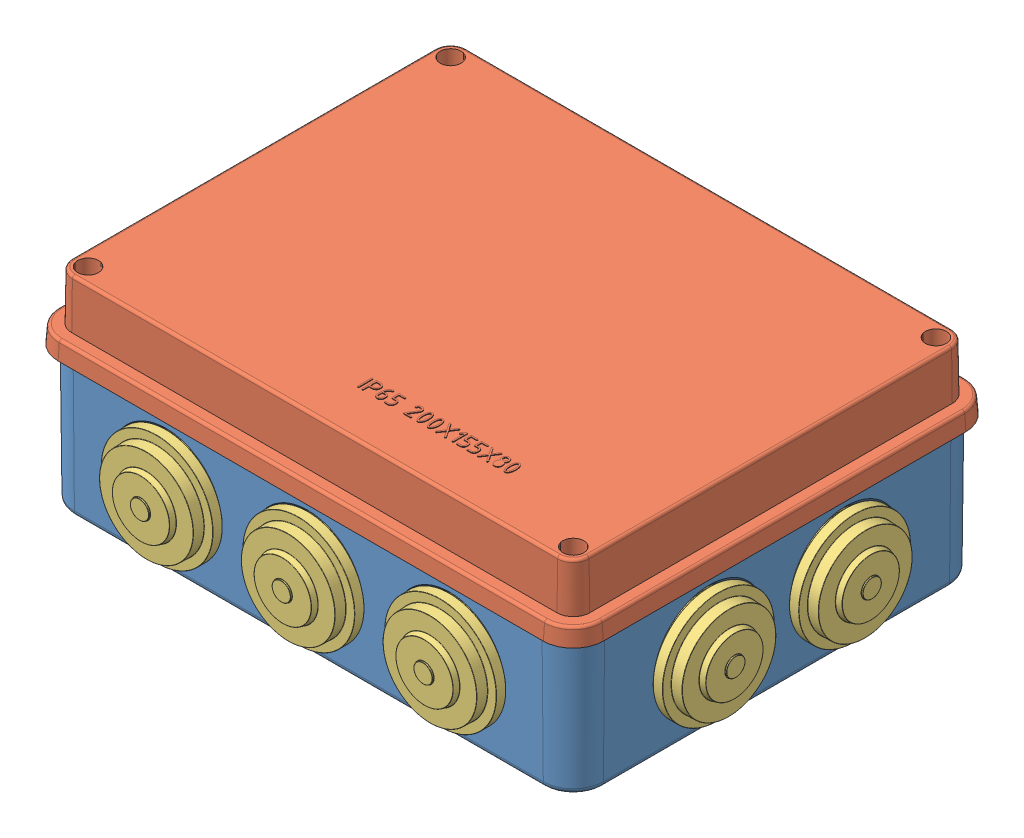
SolidWorks assembly ENCLOSURE ip67, configuration 默认. Lengths in mm.
Overall size (214.7 76.3 169.68).
17 component instances, 5 part files, 0 mates.
Components (placement in the parent):
- ENCLOSURE, IP65 ELECTRICAL ENCLOSURE, 200 mm x 155 mm x 80 mm_1-1: ENCLOSURE, IP65 ELECTRICAL ENCLOSURE, 200 mm x 155 mm x 80 mm_1 [默认] at origin size (197.16 54.12 152.16)
- ENCLOSURE COVER, IP65 ELECTRICAL ENCLOSURE, 200 mm x 155 mm x 80 mm_1-1: ENCLOSURE COVER, IP65 ELECTRICAL ENCLOSURE, 200 mm x 155 mm x 80 mm_1 [默认] at (0 49.6 0) size (200 24.71 155)
- GROMMET, IP65 ELECTRICAL ENCLOSURE, 200 mm x 155 mm x 80 mm_1-1: GROMMET, IP65 ELECTRICAL ENCLOSURE, 200 mm x 155 mm x 80 mm_1 [默认] at (0 24.6073 66.8362) x (-0.999687 0.025034 0.000241) z (0 -0.009615 0.999954) size (41 41 17.8)
- GROMMET, IP65 ELECTRICAL ENCLOSURE, 200 mm x 155 mm x 80 mm_1-2: GROMMET, IP65 ELECTRICAL ENCLOSURE, 200 mm x 155 mm x 80 mm_1 [默认] at (52 24.6073 66.8362) x (-0.999687 0.025034 0.000241) z (0 -0.009615 0.999954) size (41 41 17.8)
- GROMMET, IP65 ELECTRICAL ENCLOSURE, 200 mm x 155 mm x 80 mm_1-3: GROMMET, IP65 ELECTRICAL ENCLOSURE, 200 mm x 155 mm x 80 mm_1 [默认] at (-52 24.6073 66.8362) x (-0.999687 0.025034 0.000241) z (0 -0.009615 0.999954) size (41 41 17.8)
- GROMMET, IP65 ELECTRICAL ENCLOSURE, 200 mm x 155 mm x 80 mm_1-4: GROMMET, IP65 ELECTRICAL ENCLOSURE, 200 mm x 155 mm x 80 mm_1 [默认] at (0 24.6073 -66.8362) x (0.999687 -0.025034 0.000241) z (0 -0.009615 -0.999954) size (41 41 17.8)
- GROMMET, IP65 ELECTRICAL ENCLOSURE, 200 mm x 155 mm x 80 mm_1-5: GROMMET, IP65 ELECTRICAL ENCLOSURE, 200 mm x 155 mm x 80 mm_1 [默认] at (52 24.6073 -66.8362) x (0.999687 -0.025034 0.000241) z (0 -0.009615 -0.999954) size (41 41 17.8)
- GROMMET, IP65 ELECTRICAL ENCLOSURE, 200 mm x 155 mm x 80 mm_1-6: GROMMET, IP65 ELECTRICAL ENCLOSURE, 200 mm x 155 mm x 80 mm_1 [默认] at (-52 24.6073 -66.8362) x (0.999687 -0.025034 0.000241) z (0 -0.009615 -0.999954) size (41 41 17.8)
- GROMMET, IP65 ELECTRICAL ENCLOSURE, 200 mm x 155 mm x 80 mm_1-7: GROMMET, IP65 ELECTRICAL ENCLOSURE, 200 mm x 155 mm x 80 mm_1 [默认] at (89.3342 24.391 -25) x (-0.009571 -0.995424 -0.095073) z (0.999954 -0.009615 0) size (41 41 17.8)
- GROMMET, IP65 ELECTRICAL ENCLOSURE, 200 mm x 155 mm x 80 mm_1-8: GROMMET, IP65 ELECTRICAL ENCLOSURE, 200 mm x 155 mm x 80 mm_1 [默认] at (89.3342 24.391 25) x (0.009571 0.995424 -0.095073) z (0.999954 -0.009615 0) size (41 41 17.8)
- GROMMET, IP65 ELECTRICAL ENCLOSURE, 200 mm x 155 mm x 80 mm_1-9: GROMMET, IP65 ELECTRICAL ENCLOSURE, 200 mm x 155 mm x 80 mm_1 [默认] at (-89.3342 24.391 -25) x (-0.009571 0.995424 0.095073) z (-0.999954 -0.009615 0) size (41 41 17.8)
- GROMMET, IP65 ELECTRICAL ENCLOSURE, 200 mm x 155 mm x 80 mm_1-10: GROMMET, IP65 ELECTRICAL ENCLOSURE, 200 mm x 155 mm x 80 mm_1 [默认] at (-89.3342 24.391 25) x (0.009571 -0.995424 0.095073) z (-0.999954 -0.009615 0) size (41 41 17.8)
- O-RING, IP65 ELECTRICAL ENCLOSURE, 200 mm x 155 mm x 80 mm_1-1: O-RING, IP65 ELECTRICAL ENCLOSURE, 200 mm x 155 mm x 80 mm_1 [默认] at (0 52.1 0) x (1 0 0) z (0 -1 0) size (195 150 3)
- cross ph tapping 968_din_Screw DIN 968-ST2.9x13-C-H-N-1: cross ph tapping 968_din_Screw DIN 968-ST2.9x13-C-H-N [默认] at (-89 54.1 66.5) x (0 -1 0) z (-0.071053 0 0.997473) size (15.35 7.5 7.5)
- cross ph tapping 968_din_Screw DIN 968-ST2.9x13-C-H-N-2: cross ph tapping 968_din_Screw DIN 968-ST2.9x13-C-H-N [默认] at (89 54.1 66.5) x (0 -1 0) z (-0.071053 0 -0.997473) size (15.35 7.5 7.5)
- cross ph tapping 968_din_Screw DIN 968-ST2.9x13-C-H-N-3: cross ph tapping 968_din_Screw DIN 968-ST2.9x13-C-H-N [默认] at (-89 54.1 -66.5) x (0 -1 0) z (0.071053 0 0.997473) size (15.35 7.5 7.5)
- cross ph tapping 968_din_Screw DIN 968-ST2.9x13-C-H-N-4: cross ph tapping 968_din_Screw DIN 968-ST2.9x13-C-H-N [默认] at (89 54.1 -66.5) x (0 -1 0) z (0.071053 0 -0.997473) size (15.35 7.5 7.5)
